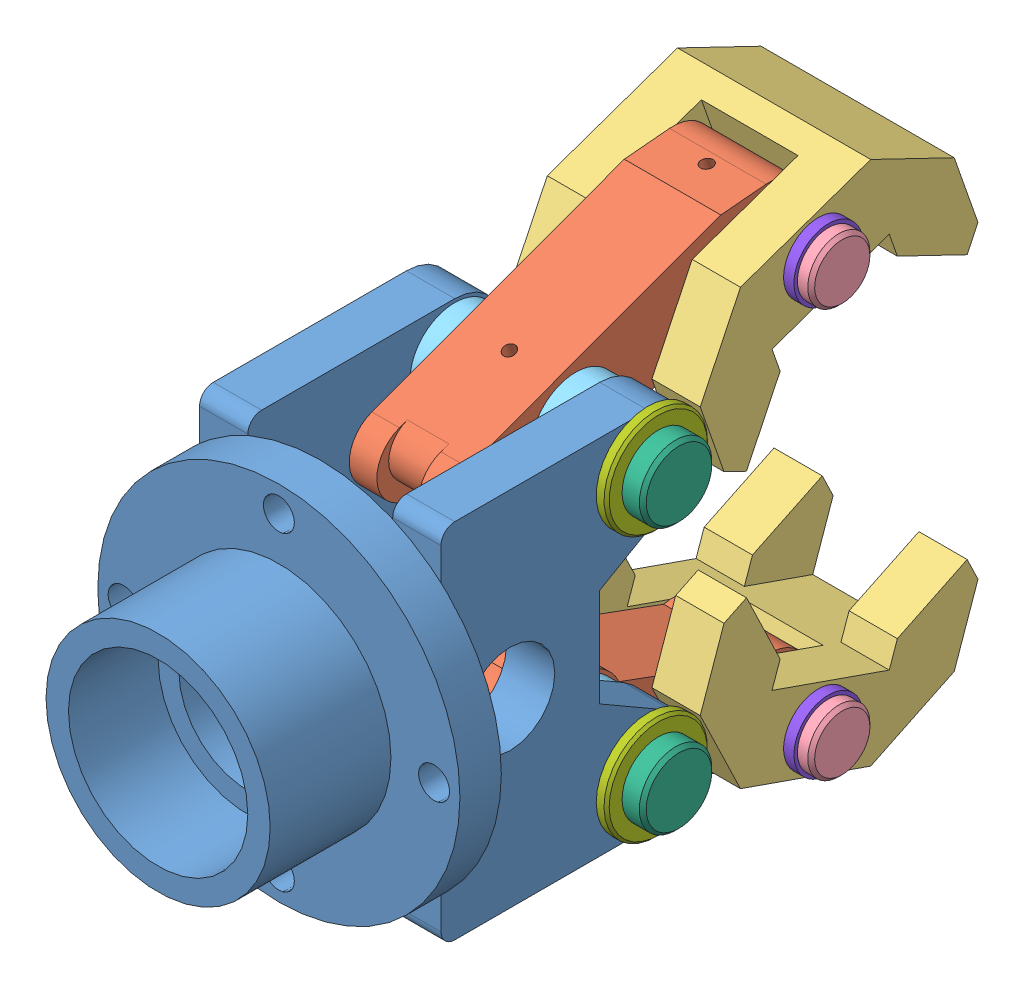
SolidWorks assembly joint7, configuration 默认. Lengths in mm.
Overall size (105 164.84 211.36).
17 component instances, 8 part files, 15 mates.
Components (placement in the parent):
- 14-1: 14 [默认] at origin size (105 105 164.01)
- 18-1: 18 [默认] at (0 38.5 -107) x (0 0.344424 -0.938814) z (1 0 0) size (111.06 36.13 28)
- 19-1: 19 [默认] at (0 69.5489 -159.698) x (0 0.330078 -0.943954) z (1 0 0) size (82.89 45 56.5)
- 22-1: 22 [默认] at (35 59.1654 -163.3289) x (0 -0.811761 -0.583989) z (-1 0 0) size (18 18 66)
- 24-1: 24 [默认] at (-21 38.5 -107) x (0 -0.533782 -0.845622) z (1 0 0) size (26 26 7)
- 25-1: 25 [默认] at (44 38.5 -107) x (-1 0 0) z (0 -0.659078 -0.752075) size (82 21 21)
- 24-2: 24 [默认] at (21 38.5 -107) x (0 -0.699829 -0.71431) z (-1 0 0) size (26 26 7)
- 26-1: 26 [默认] at (26.3555 38.5 -107) x (0 -0.33616 0.941805) z (0 0.941805 0.33616) size (45 11.64 30)
- 23-1: 23 [默认] at (28 59.1654 -163.3289) x (0 -0.043815 -0.99904) z (1 0 0) size (20 20 3)
- 19-2: 19 [默认] at (0 -69.5489 -159.698) x (0 -0.330078 -0.943954) z (-1 0 0) size (82.89 45 56.5)
- 18-2: 18 [默认] at (0 -38.5 -107) x (0 -0.344424 -0.938814) z (-1 0 0) size (111.06 36.13 28)
- 22-2: 22 [默认] at (35 -59.1654 -163.3289) x (0 -0.811761 0.583989) z (-1 0 0) size (18 18 66)
- 23-2: 23 [默认] at (31 -59.1654 -163.3289) x (0 0.043815 -0.99904) z (-1 0 0) size (20 20 3)
- 25-2: 25 [默认] at (44 -38.5 -107) x (-1 0 0) z (0 -0.659078 0.752075) size (82 21 21)
- 26-2: 26 [默认] at (26.3555 -38.5 -107) x (0 0.33616 0.941805) z (0 0.941805 -0.33616) size (45 11.64 30)
- 24-4: 24 [默认] at (14 -38.5 -107) x (0 0.699829 -0.71431) z (1 0 0) size (26 26 7)
- 24-5: 24 [默认] at (-14 -38.5 -107) x (0 0.533782 -0.845622) z (-1 0 0) size (26 26 7)
Mates (geometry in assembly coordinates):
- 同心2: concentric aligned: cylinder of 14-1 through (-52.5 38.5 -107) axis (1 0 0) radius 8; cylinder of 18-1 through (-14 38.5 -107) axis (1 0 0) radius 8
- 同心3: concentric anti-aligned: circle of 14-1; cylinder of 24-1 through (-14 38.5 -107) axis (-1 0 0) radius 8.1
- 重合1: coincident anti-aligned: plane of 14-1 through (-21 38.5 -107) normal (1 0 0); plane of 24-1 through (-21 38.5 -107) normal (-1 0 0)
- 同心4: concentric aligned: cylinder of 14-1 through (-52.5 38.5 -107) axis (1 0 0) radius 8; cylinder of 24-2 through (14 38.5 -107) axis (1 0 0) radius 8.1
- 重合2: coincident anti-aligned: plane of 14-1 through (21 38.5 -107) normal (-1 0 0); plane of 24-2 through (21 38.5 -107) normal (1 0 0)
- 重合3: coincident anti-aligned: plane of 18-1 through (-14 38.5 -107) normal (-1 0 0); plane of 24-1 through (-14 38.5 -107) normal (1 0 0)
- 重合4: coincident anti-aligned: plane of 14-1 through (35 38.5 -107) normal (1 0 0); plane of 26-1 through (35 41.3574 -115.0053) normal (-1 0 0)
- 同心7: concentric anti-aligned: cylinder of 18-1 through (-14 59.1654 -163.3289) axis (1 0 0) radius 6.5; cylinder of 19-1 through (28 59.1654 -163.3289) axis (-1 0 0) radius 4.7815
- 同心8: concentric anti-aligned: cylinder of 14-1 through (-52.5 38.5 -107) axis (1 0 0) radius 8; cylinder of 25-1 through (-38 38.5 -107) axis (-1 0 0) radius 8
- 重合6: coincident anti-aligned: plane of 25-1 through (38 38.5 -107) normal (-1 0 0); plane of 26-1 through (38 41.3574 -115.0053) normal (1 0 0)
- 同心9: concentric anti-aligned: cylinder of 19-1 through (28 59.1654 -163.3289) axis (-1 0 0) radius 4.7815; cylinder of 22-1 through (-31 59.1654 -163.3289) axis (1 0 0) radius 6.5
- 同心10: concentric anti-aligned: cylinder of 22-1 through (-31 59.1654 -163.3289) axis (1 0 0) radius 6.5; cylinder of 23-1 through (31 59.1654 -163.3289) axis (-1 0 0) radius 6.5
- 重合7: coincident anti-aligned: plane of 19-1 through (28 69.5489 -159.698) normal (1 0 0); plane of 23-1 through (28 59.1654 -163.3289) normal (-1 0 0)
- 重合8: coincident anti-aligned: plane of 22-1 through (31 59.1654 -163.3289) normal (-1 0 0); plane of 23-1 through (31 59.1654 -163.3289) normal (1 0 0)
- 重合9: coincident anti-aligned: plane of 18-1 through (14 38.5 -107) normal (1 0 0); plane of 19-1 through (14 14.2003 -137.7365) normal (-1 0 0)
